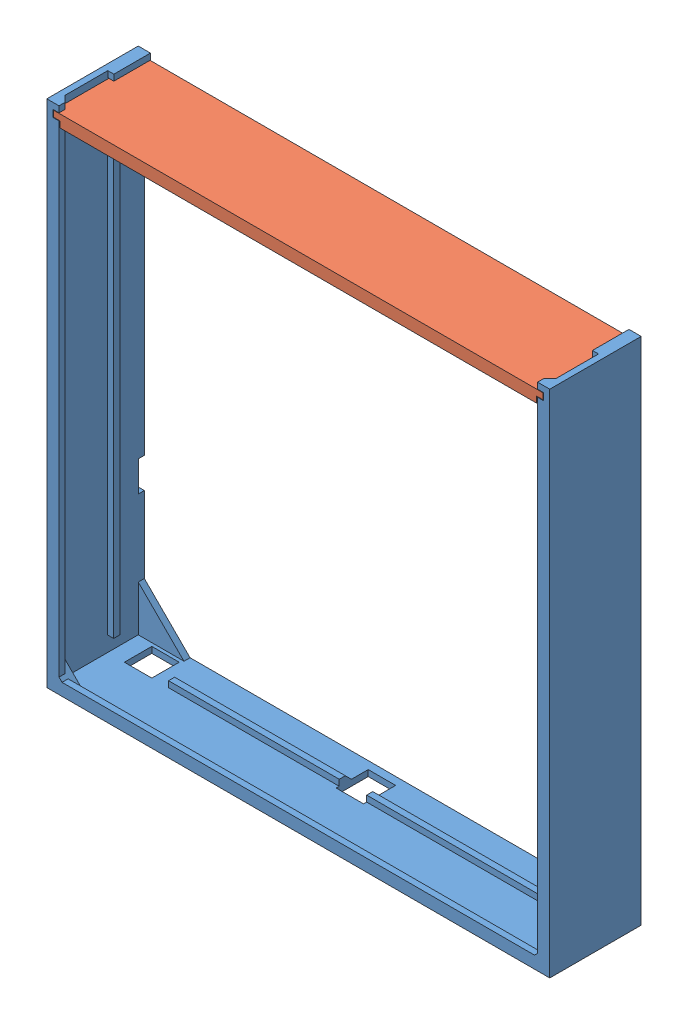
SolidWorks assembly Matrix_Assem_V2, configuration Default. Lengths in mm.
Overall size (209.55 212.47 38.1).
2 component instances, 2 part files, 1 mates.
Components (placement in the parent):
- Sides-1: Sides [Default] at (71.6174 115.5907 140.5138) size (209.55 212.47 38.1)
- Top-1: Top [Default] at (71.5921 220.5784 159.5638) x (-1 0 0) z (0 0 1) size (203.83 5.08 38.1)
Mates (geometry in assembly coordinates):
- Coincident1: coincident aligned: plane of Sides-1 through (71.6174 115.5907 178.6138) normal (0 0 1); plane of Top-1 through (-30.3254 218.0384 178.6138) normal (0 0 1)
